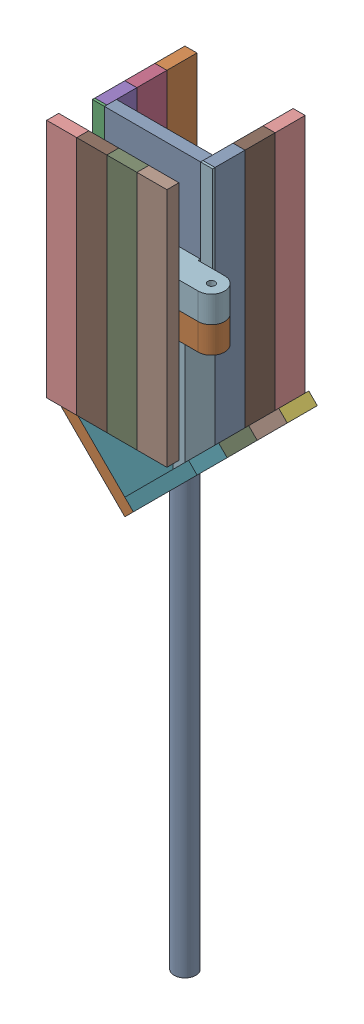
SolidWorks assembly Beach Hut Violet_1, configuration Défaut. Lengths in mm.
Overall size (132.1 615 113.42).
11 component instances, 11 part files, 0 mates.
Components (placement in the parent):
- Beach hut - Matt-1: Beach hut - Matt [Défaut] at (-308.4913 -626.3682 198.8389) x (-0.87546 0 0.48329) z (-0.48329 0 -0.87546) size (18 500 18)
- Beach hut - Roof 2-1: Beach hut - Roof 2 [Défaut] at (-338.5433 -245.4583 161.3389) x (0 0 1) z (-0.707107 0.707107 0) size (100 10 85)
- Beach hut - Roof 1-1: Beach hut - Roof 1 [Défaut] at (-281.9748 -234.8517 161.3389) x (0 0 1) z (0.707107 0.707107 0) size (100 10 75)
- Beach hut - Wall 1-1: Beach hut - Wall 1 [Défaut] at (-258.4913 -116.3682 161.3389) x (0 0 1) z (0 -1 0) size (100 10 210)
- Beach hut - Wall 2-1: Beach hut - Wall 2 [Défaut] at (-358.4913 -116.3682 161.3389) x (0 0 1) z (0 -1 0) size (100 10 210)
- Beach hut - Wall back-1: Beach hut - Wall back [Défaut] at (-308.4913 -161.3682 148.8389) x (-1 0 0) z (0 0 1) size (80 100 10)
- Beach hut - Wall front-1: Beach hut - Wall front [Défaut] at (-308.4913 -126.3682 238.8389) x (-1 0 0) z (0 0 1) size (80 135 10)
- Beach hut - door-1: Beach hut - door [Défaut] at (-275.9913 -112.3682 248.8389) x (-1 0 0) z (0 1 0) size (100 10 200)
- Beach hut - Door 2-1: Beach hut - Door 2 [Défaut] at (-247.4913 -104.3682 237.8389) x (0 0 1) z (-1 0 0) size (103.42 22 106)
- Beach hut - Wall 3-1: Beach hut - Wall 3 [Défaut] at (-308.4913 -81.3682 215.8389) size (80 70 10)
- Beach hut - Ground-1: Beach hut - Ground [Défaut] at (-308.4913 -104.3682 198.8389) x (-1 0 0) z (0 0 1) size (112 22 100)
